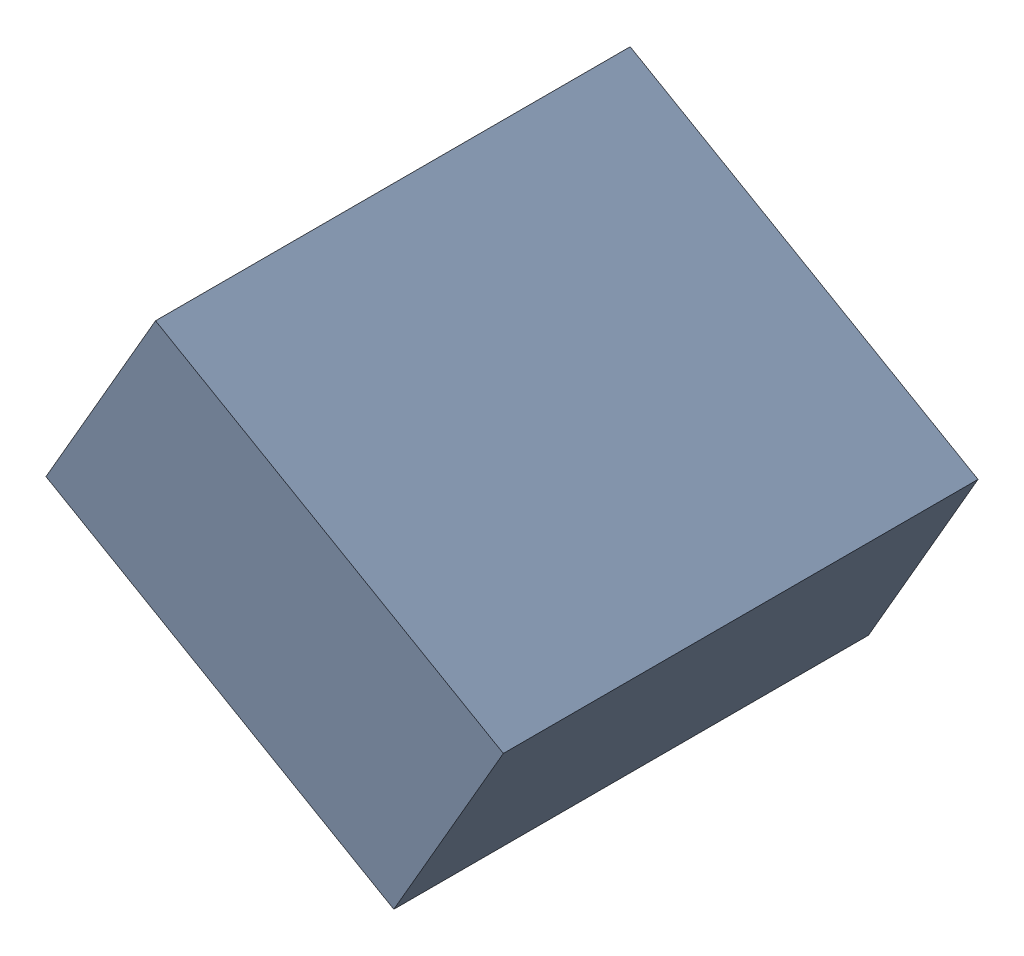
SolidWorks assembly C25_TDA3, configuration Standard. Lengths in mm.
Overall size (1.25 1.07 1.3).
2 component instances, 1 part files, 0 mates.
Components (placement in the parent):
- 885543056-1: 885543056 [Standard] at (34.0607 -24.8964 0) size (1.25 1.07 1.3)
  - Extruded_23-1: Extruded_23 [Standard] at origin size (1.25 1.07 1.3)
